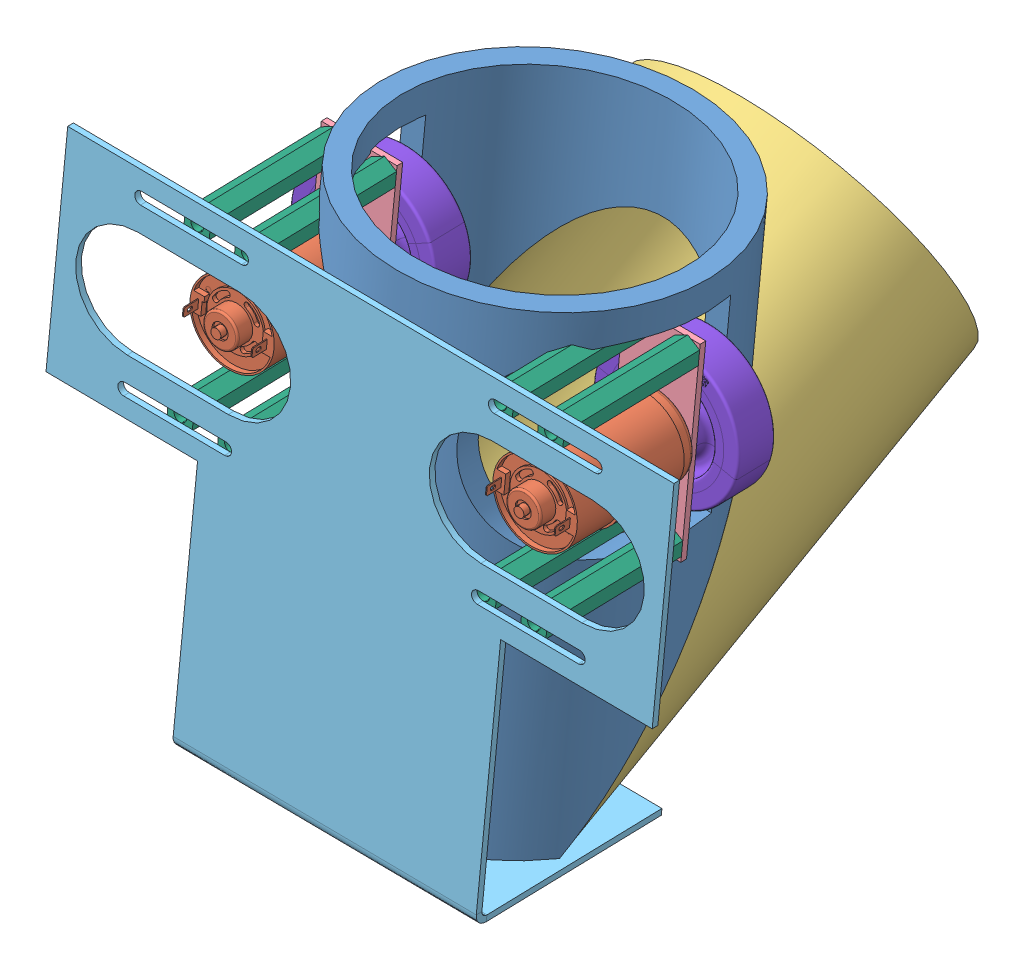
SolidWorks assembly Shooter 1]2ASmMK2, configuration Default. Lengths in mm.
Overall size (325.73 301.67 311.41).
19 component instances, 8 part files, 50 mates.
Components (placement in the parent):
- barrellMk2-1: barrellMk2 [Default] at (-143.63 576.6437 294.5073) x (0.996255 -0.066286 -0.055525) z (-0.064337 -0.997272 0.036194) size (166.95 166.95 255.27)
- Vex217-4347-STEP-20160210MK2-1: Vex217-4347-STEP-20160210MK2 [Default] at (-217.8208 593.3442 315.7602) x (0.057773 0.032486 0.997801) z (-0.064337 -0.997272 0.036194) size (88 44.3 44.3)
- Vex217-4347-STEP-20160210MK2-2: Vex217-4347-STEP-20160210MK2 [Default] at (-65.9916 583.2422 307.2982) x (0.057773 0.032486 0.997801) z (0.064337 0.997272 -0.036194) size (88 44.3 44.3)
- barrellFeederMk2-1: barrellFeederMk2 [Default] at (-150.1568 475.6316 297.9903) x (-0.996255 0.066286 0.055525) z (0.017864 -0.470502 0.882218) size (166.95 166.95 254)
- SpinMotorSideMk2-3: SpinMotorSideMk2 [Default] at (-217.8208 593.3442 315.7602) x (-0.064337 -0.997272 0.036194) z (0.996255 -0.066286 -0.055525) size (101.6 3.17 38.1)
- SpinMotorSideMk2-5: SpinMotorSideMk2 [Default] at (-66.175 583.1391 304.1302) x (0.064337 0.997272 -0.036194) z (0.996255 -0.066286 -0.055525) size (101.6 3.17 38.1)
- SpinMotorMk2-1: SpinMotorMk2 [Default] at (-137.3205 590.8718 390.7297) x (0.996255 -0.066286 -0.055525) z (0.064337 0.997272 -0.036194) size (304.8 104.77 248.92)
- Mackchurro-2: Mackchurro [Default] at (-231.1319 551.095 356.0905) x (-0.89495 -0.44123 0.066183) z (0.44241 -0.896806 0.003583) size (14.66 76.2 12.7)
- Mackchurro-3: Mackchurro [Default] at (-200.1075 638.0688 351.4625) x (0.064337 0.997272 -0.036194) z (-0.996255 0.066286 0.055525) size (14.66 76.2 12.7)
- Mackchurro-4: Mackchurro [Default] at (-205.827 549.4114 354.6801) x (0.064337 0.997272 -0.036194) z (-0.996255 0.066286 0.055525) size (14.66 76.2 12.7)
- Mackchurro-5: Mackchurro [Default] at (-225.4123 639.7525 352.8728) x (0.064337 0.997272 -0.036194) z (-0.996255 0.066286 0.055525) size (14.66 76.2 12.7)
- Mackchurro-6: Mackchurro [Default] at (-48.2783 627.9668 343.0005) x (0.89495 0.44123 -0.066183) z (-0.44241 0.896806 -0.003583) size (14.66 76.2 12.7)
- Mackchurro-7: Mackchurro [Default] at (-53.9978 539.3094 346.2181) x (0.89495 0.44123 -0.066183) z (0.44241 -0.896806 0.003583) size (14.66 76.2 12.7)
- Mackchurro-8: Mackchurro [Default] at (-79.3027 540.993 347.6285) x (0.064337 0.997272 -0.036194) z (0.996255 -0.066286 -0.055525) size (14.66 76.2 12.7)
- Mackchurro-9: Mackchurro [Default] at (-73.5831 629.6505 344.4108) x (0.064337 0.997272 -0.036194) z (0.996255 -0.066286 -0.055525) size (14.66 76.2 12.7)
- Hub_T81H-RM51-1: Hub_T81H-RM51 [Default] at (-218.2564 593.0993 308.2368) x (0.899564 0.431752 -0.066142) z (-0.057773 -0.032486 -0.997801) size (20.32 20.32 20.32)
- Wheel_T81P-29-1: Wheel_T81P-29 [Default] at (-218.2564 593.0993 308.2368) x (-0.899564 -0.431752 0.066142) z (-0.057773 -0.032486 -0.997801) size (73.03 73.03 21.34)
- Wheel_T81P-29-2: Wheel_T81P-29 [Default] at (-66.4272 582.9973 299.7748) x (-0.962819 0.266013 0.047086) z (-0.057773 -0.032486 -0.997801) size (73.03 73.03 21.34)
- Hub_T81H-RM51-2: Hub_T81H-RM51 [Default] at (-66.4272 582.9973 299.7748) x (0.263898 0.963422 -0.046647) z (-0.057773 -0.032486 -0.997801) size (20.32 20.32 20.32)
Mates (geometry in assembly coordinates):
- Coincident100: coincident anti-aligned: plane of barrellMk2-1 through (-147.8058 549.8838 251.5293) normal (-0.082201 -0.52677 -0.846024); plane of barrellFeederMk2-1 through (-150.1568 475.6316 297.9903) normal (0.082201 0.52677 0.846024)
- Coincident101: coincident anti-aligned: plane of barrellMk2-1; plane of barrellFeederMk2-1
- Coincident102: coincident aligned: plane of barrellMk2-1 through (-155.0486 399.6455 300.9312) normal (-0.064337 -0.997272 0.036194); plane of barrellFeederMk2-1 through (-155.0592 399.6395 300.7483) normal (-0.064337 -0.997272 0.036194)
- Coincident108: coincident anti-aligned: plane of barrellMk2-1 through (-228.3389 543.1652 318.003) normal (-0.057773 -0.032486 -0.997801); plane of SpinMotorSideMk2-3 through (-217.8208 593.3442 315.7602) normal (0.057773 0.032486 0.997801)
- Concentric50: concentric aligned: cylinder of Vex217-4347-STEP-20160210MK2-1 through (-217.8208 593.3442 315.7602) axis (-0.057773 -0.032486 -0.997801) radius 8.9; cylinder of SpinMotorSideMk2-3 through (-217.8208 593.3442 315.7602) axis (-0.057773 -0.032486 -0.997801) radius 9.525
- Concentric51: concentric aligned: cylinder of Vex217-4347-STEP-20160210MK2-1 through (-203.3751 592.3831 314.9551) axis (-0.057773 -0.032486 -0.997801) radius 1.65; cylinder of SpinMotorSideMk2-3 through (-203.3751 592.3831 314.9551) axis (-0.057773 -0.032486 -0.997801) radius 1.778
- Coincident109: coincident anti-aligned: plane of Vex217-4347-STEP-20160210MK2-1 through (-226.6875 593.9342 316.2544) normal (-0.057773 -0.032486 -0.997801); plane of SpinMotorSideMk2-3 through (-217.8208 593.3442 315.7602) normal (0.057773 0.032486 0.997801)
- Width16: width anti-aligned: plane of SpinMotorSideMk2-3 through (-221.0891 542.6828 317.5989) normal (-0.064337 -0.997272 0.036194); plane of SpinMotorSideMk2-3 through (-214.5525 644.0056 313.9216) normal (0.064337 0.997272 -0.036194); plane of barrellMk2-1 through (-228.5224 543.062 314.8349) normal (0.064337 0.997272 -0.036194); plane of barrellMk2-1 through (-221.9858 644.3848 311.1576) normal (-0.064337 -0.997272 0.036194)
- Coincident112: coincident anti-aligned: plane of barrellMk2-1 through (-228.3389 543.1652 318.003) normal (-0.057773 -0.032486 -0.997801); plane of SpinMotorSideMk2-5 through (-65.9916 583.2422 307.2982) normal (0.057773 0.032486 0.997801)
- Coincident113: coincident anti-aligned: plane of barrellMk2-1 through (-228.5224 543.062 314.8349) normal (0.064337 0.997272 -0.036194); plane of SpinMotorSideMk2-5 through (-69.4433 532.4777 305.9689) normal (-0.064337 -0.997272 0.036194)
- Concentric53: concentric anti-aligned: cylinder of Vex217-4347-STEP-20160210MK2-2 through (-65.9916 583.2422 307.2982) axis (-0.057773 -0.032486 -0.997801) radius 8.9; cylinder of SpinMotorSideMk2-5 through (-66.175 583.1391 304.1302) axis (0.057773 0.032486 0.997801) radius 9.525
- Concentric54: concentric anti-aligned: cylinder of Vex217-4347-STEP-20160210MK2-2 through (-51.5459 582.281 306.4931) axis (-0.057773 -0.032486 -0.997801) radius 1.65; cylinder of SpinMotorSideMk2-5 through (-51.7293 582.1779 303.3251) axis (0.057773 0.032486 0.997801) radius 1.778
- Coincident114: coincident anti-aligned: plane of Vex217-4347-STEP-20160210MK2-2 through (-57.1249 582.6523 306.8041) normal (-0.057773 -0.032486 -0.997801); plane of SpinMotorSideMk2-5 through (-65.9916 583.2422 307.2982) normal (0.057773 0.032486 0.997801)
- Concentric60: concentric anti-aligned: cylinder of SpinMotorSideMk2-3 through (-233.333 549.8573 318.0742) axis (-0.057773 -0.032486 -0.997801) radius 3.175; cylinder of Mackchurro-2 through (-233.333 549.8573 318.0742) axis (0.057773 0.032486 0.997801) radius 3.175
- Coincident123: coincident anti-aligned: plane of SpinMotorSideMk2-3 through (-217.8208 593.3442 315.7602) normal (0.057773 0.032486 0.997801); plane of Mackchurro-2 through (-233.333 549.8573 318.0742) normal (-0.057773 -0.032486 -0.997801)
- Coincident124: coincident anti-aligned: plane of SpinMotorSideMk2-3 through (-217.8208 593.3442 315.7602) normal (0.057773 0.032486 0.997801); plane of Mackchurro-5 through (-227.6135 638.5148 314.8566) normal (-0.057773 -0.032486 -0.997801)
- Coincident125: coincident aligned: cylinder of SpinMotorSideMk2-3 through (-227.6135 638.5148 314.8566) axis (-0.057773 -0.032486 -0.997801) radius 3.175; circle of Mackchurro-5
- Concentric61: concentric anti-aligned: cylinder of SpinMotorSideMk2-3 through (-202.3086 636.8311 313.4462) axis (-0.057773 -0.032486 -0.997801) radius 3.175; cylinder of Mackchurro-3 through (-202.3086 636.8311 313.4462) axis (0.057773 0.032486 0.997801) radius 3.175
- Coincident126: coincident anti-aligned: plane of SpinMotorSideMk2-3 through (-217.8208 593.3442 315.7602) normal (0.057773 0.032486 0.997801); plane of Mackchurro-3 through (-202.3086 636.8311 313.4462) normal (-0.057773 -0.032486 -0.997801)
- Coincident127: coincident anti-aligned: circle of SpinMotorSideMk2-3; cylinder of Mackchurro-4 through (-208.0281 548.1736 316.6639) axis (0.057773 0.032486 0.997801) radius 3.175
- Coincident128: coincident anti-aligned: plane of SpinMotorSideMk2-3 through (-217.8208 593.3442 315.7602) normal (0.057773 0.032486 0.997801); plane of Mackchurro-4 through (-208.0281 548.1736 316.6639) normal (-0.057773 -0.032486 -0.997801)
- Coincident130: coincident anti-aligned: circle of SpinMotorSideMk2-5; cylinder of Mackchurro-9 through (-71.382 630.8882 382.427) axis (-0.057773 -0.032486 -0.997801) radius 3.175
- Coincident131: coincident anti-aligned: plane of SpinMotorSideMk2-5 through (-65.9916 583.2422 307.2982) normal (0.057773 0.032486 0.997801); plane of Mackchurro-9 through (-75.7843 628.4128 306.3946) normal (-0.057773 -0.032486 -0.997801)
- Coincident132: coincident anti-aligned: cylinder of SpinMotorSideMk2-5 through (-50.6628 626.6259 301.8162) axis (0.057773 0.032486 0.997801) radius 3.175; circle of Mackchurro-6
- Coincident133: coincident anti-aligned: plane of SpinMotorSideMk2-5 through (-65.9916 583.2422 307.2982) normal (0.057773 0.032486 0.997801); plane of Mackchurro-6 through (-50.4794 626.7291 304.9842) normal (-0.057773 -0.032486 -0.997801)
- Coincident134: coincident anti-aligned: circle of SpinMotorSideMk2-5; cylinder of Mackchurro-8 through (-77.1015 542.2308 385.6447) axis (-0.057773 -0.032486 -0.997801) radius 3.175
- Coincident135: coincident anti-aligned: circle of SpinMotorSideMk2-5; cylinder of Mackchurro-7 through (-51.7967 540.5471 384.2344) axis (-0.057773 -0.032486 -0.997801) radius 3.175
- Coincident136: coincident: plane of SpinMotorSideMk2-5 through (-65.9916 583.2422 307.2982) normal (0.057773 0.032486 0.997801); moEndPointRef_w of Mackchurro-7
- Coincident137: coincident anti-aligned: plane of SpinMotorSideMk2-5 through (-65.9916 583.2422 307.2982) normal (0.057773 0.032486 0.997801); plane of Mackchurro-8 through (-81.5038 539.7553 309.6122) normal (-0.057773 -0.032486 -0.997801)
- Coincident138: coincident aligned: plane of barrellMk2-1; plane of SpinMotorMk2-1
- Coincident139: coincident aligned: plane of Mackchurro-3 through (-195.7465 640.0664 312.961) normal (0.996255 -0.066286 -0.055525); plane of Mackchurro-4 through (-201.466 551.4089 316.1786) normal (0.996255 -0.066286 -0.055525)
- Coincident140: coincident aligned: plane of Mackchurro-2 through (-226.7709 553.0926 317.589) normal (0.996255 -0.066286 -0.055525); plane of Mackchurro-5 through (-221.0514 641.75 314.3713) normal (0.996255 -0.066286 -0.055525)
- Coincident141: coincident aligned: plane of Mackchurro-6 through (-43.9173 629.9643 304.499) normal (0.996255 -0.066286 -0.055525); plane of Mackchurro-7 through (-45.7063 536.47 384.0145) normal (0.996255 -0.066286 -0.055525)
- Coincident142: coincident aligned: plane of Mackchurro-8 through (-71.0112 538.1537 385.4248) normal (0.996255 -0.066286 -0.055525); plane of Mackchurro-9 through (-65.2917 626.8111 382.2071) normal (0.996255 -0.066286 -0.055525)
- Coincident143: coincident anti-aligned: plane of barrellFeederMk2-1 through (-155.0592 399.6395 300.7483) normal (-0.064337 -0.997272 0.036194); plane of SpinMotorMk2-1 through (-231.4218 404.4386 297.2421) normal (0.064337 0.997272 -0.036194)
- Slot1: slot anti-aligned: cylinder of Mackchurro-5 through (-227.6135 638.5148 314.8566) axis (0.057773 0.032486 0.997801) radius 3.175; plane of SpinMotorMk2-1 through (-248.7203 639.5076 392.4143) normal (0.064337 0.997272 -0.036194); cylinder of SpinMotorMk2-1 through (-197.9063 639.3066 389.4787) axis (-0.057773 -0.032486 -0.997801) radius 3.175
- Slot2: slot anti-aligned: cylinder of Mackchurro-3 through (-202.3086 636.8311 313.4462) axis (0.057773 0.032486 0.997801) radius 3.175; cylinder of SpinMotorMk2-1 through (-197.9063 639.3066 389.4787) axis (-0.057773 -0.032486 -0.997801) radius 3.175; cylinder of SpinMotorMk2-1 through (-248.5161 642.6739 392.2993) axis (-0.057773 -0.032486 -0.997801) radius 3.175
- Coincident144: coincident anti-aligned: plane of SpinMotorMk2-1 through (-137.5039 590.7687 387.5617) normal (-0.057773 -0.032486 -0.997801); plane of Mackchurro-3 through (-197.9063 639.3066 389.4787) normal (0.057773 0.032486 0.997801)
- Concentric62: concentric aligned: cylinder of Vex217-4347-STEP-20160210MK2-1 through (-217.8208 593.3442 315.7602) axis (-0.057773 -0.032486 -0.997801) radius 2.5; cylinder of Hub_T81H-RM51-1 through (-218.2711 593.091 307.9834) axis (-0.057773 -0.032486 -0.997801) radius 2.5
- Distance2: distance = 2.54 mm anti-aligned: plane of Vex217-4347-STEP-20160210MK2-1 through (-220.6003 593.3475 310.91) normal (-0.057773 -0.032486 -0.997801); plane of Hub_T81H-RM51-1 through (-207.4032 598.3084 307.4388) normal (0.057773 0.032486 0.997801)
- Coincident147: coincident anti-aligned: plane of Hub_T81H-RM51-1 through (-225.0191 582.5998 301.3334) normal (-0.899564 -0.431752 0.066142); plane of Wheel_T81P-29-1 through (-230.6533 594.3304 301.2777) normal (0.899564 0.431752 -0.066142)
- Tangent3: tangent: face of Hub_T81H-RM51-1; plane of Wheel_T81P-29-1 through (-205.1583 588.08 300.0051) normal (0.057773 0.032486 0.997801)
- Coincident149: coincident anti-aligned: plane of Wheel_T81P-29-1 through (-220.1511 580.8841 301.1074) normal (-0.432952 0.901407 -0.00428); plane of Hub_T81H-RM51-1 through (-208.4445 586.5028 300.2467) normal (0.432952 -0.901407 0.00428)
- Concentric63: concentric aligned: cylinder of Vex217-4347-STEP-20160210MK2-2 through (-65.9916 583.2422 307.2982) axis (-0.057773 -0.032486 -0.997801) radius 2.5; cylinder of Hub_T81H-RM51-2 through (-66.4419 582.989 299.5214) axis (-0.057773 -0.032486 -0.997801) radius 2.5
- Distance1: distance = 2.54 mm anti-aligned: plane of Vex217-4347-STEP-20160210MK2-2 through (-63.7898 582.9141 302.1704) normal (-0.057773 -0.032486 -0.997801); plane of Hub_T81H-RM51-2 through (-63.2433 594.6209 299.212) normal (0.057773 0.032486 0.997801)
- Coincident151: coincident anti-aligned: plane of Wheel_T81P-29-2 through (-59.7664 570.2587 292.1671) normal (0.057773 0.032486 0.997801); circle of Hub_T81H-RM51-2
- Coincident152: coincident anti-aligned: plane of Wheel_T81P-29-2 through (-74.9325 591.7212 292.3465) normal (0.962819 -0.266013 -0.047086); plane of Hub_T81H-RM51-2 through (-78.3668 579.1836 292.9535) normal (-0.962819 0.266013 0.047086)
- Coincident153: coincident anti-aligned: plane of Wheel_T81P-29-2 through (-75.8135 574.6922 292.9519) normal (0.263898 0.963422 -0.046647); plane of Hub_T81H-RM51-2 through (-63.2838 571.2304 292.3391) normal (-0.263898 -0.963422 0.046647)
- Slot5: slot anti-aligned: cylinder of Mackchurro-6 through (-50.4794 626.7291 304.9842) axis (0.057773 0.032486 0.997801) radius 3.175; plane of SpinMotorMk2-1 through (-20.7931 624.4577 382.8893) normal (0.064337 0.997272 -0.036194); cylinder of SpinMotorMk2-1 through (-71.1986 630.9914 385.595) axis (-0.057773 -0.032486 -0.997801) radius 3.175
- Slot6: slot aligned: cylinder of Mackchurro-9 through (-71.382 630.8882 382.427) axis (-0.057773 -0.032486 -0.997801) radius 3.175; plane of SpinMotorMk2-1 through (-20.7931 624.4577 382.8893) normal (0.064337 0.997272 -0.036194); cylinder of SpinMotorMk2-1 through (-71.1986 630.9914 385.595) axis (-0.057773 -0.032486 -0.997801) radius 3.175
